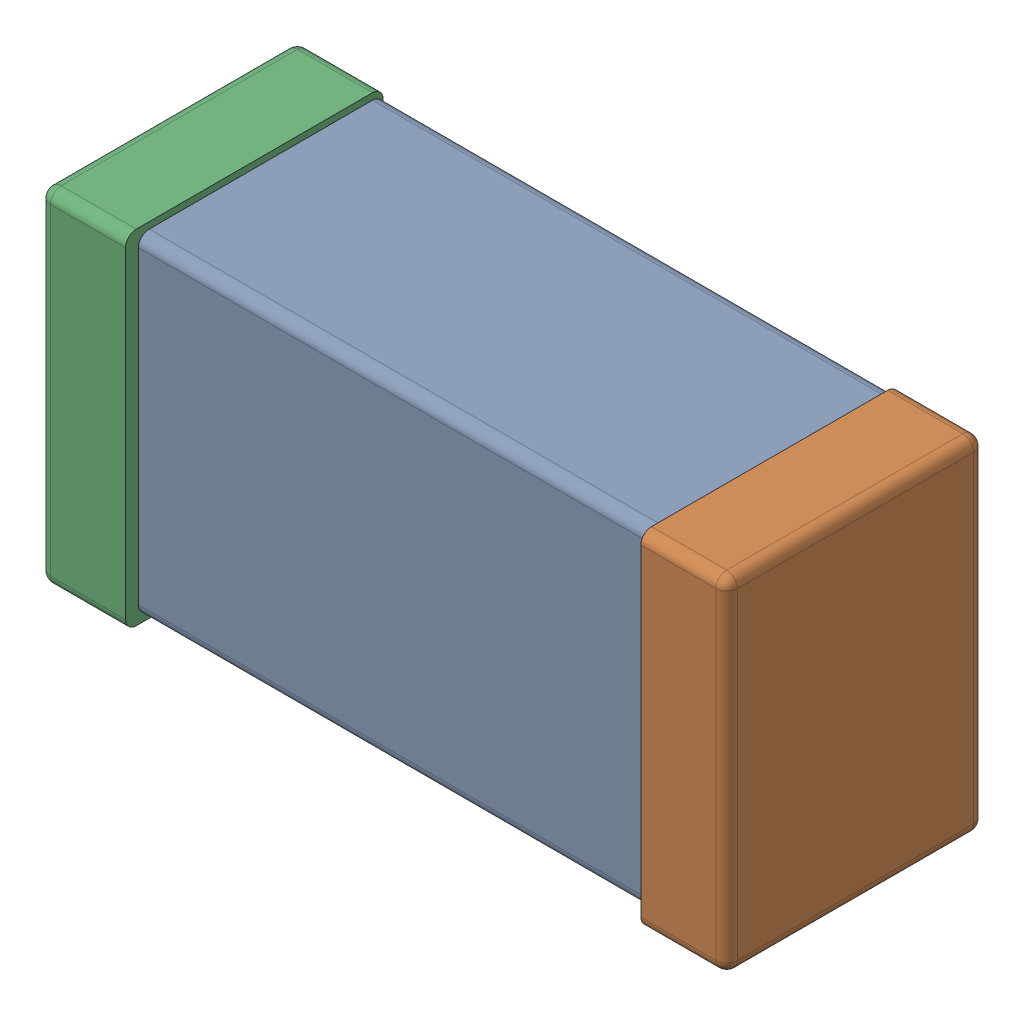
SolidWorks assembly C0603_060_7, configuration Standard. Lengths in mm.
Overall size (1.6 0.8 0.6).
3 component instances, 3 part files, 0 mates.
Components (placement in the parent):
- Part 3_1-1: Part 3_1 [Standard] at (0 0 -23.815) size (1.4 0.77 0.57)
- Part 2_1-1: Part 2_1 [Standard] at (0 0 -23.8) size (0.2 0.8 0.6)
- Part 1_1-1: Part 1_1 [Standard] at (0 0 -23.8) size (0.2 0.8 0.6)
